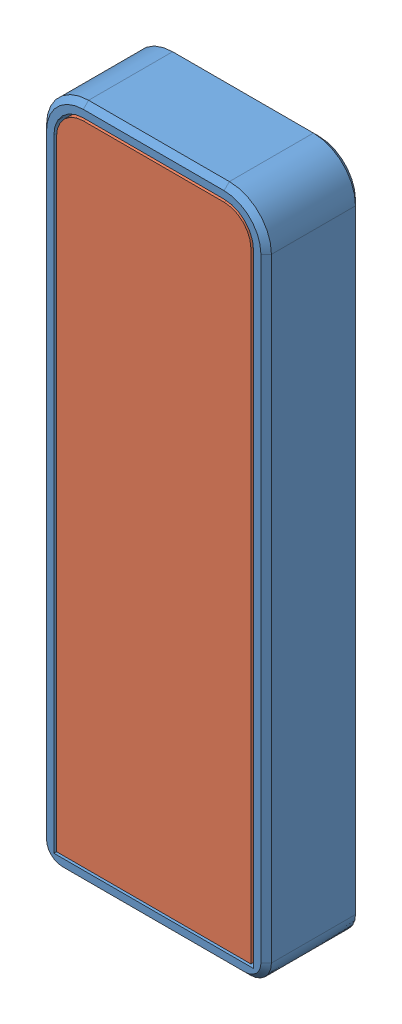
SolidWorks assembly HUB_ASSAMBLY, configuration Standard. Lengths in mm.
Overall size (21.4 65.31 9).
2 component instances, 2 part files, 0 mates.
Components (placement in the parent):
- HUB_CASE_BASE-1: HUB_CASE_BASE [Standard] at (-70.4575 9.232 -4.5) size (21.4 65.31 9)
- HUB_BACK-1: HUB_BACK [Standard] at origin size (19.8 61.5 1.9)
